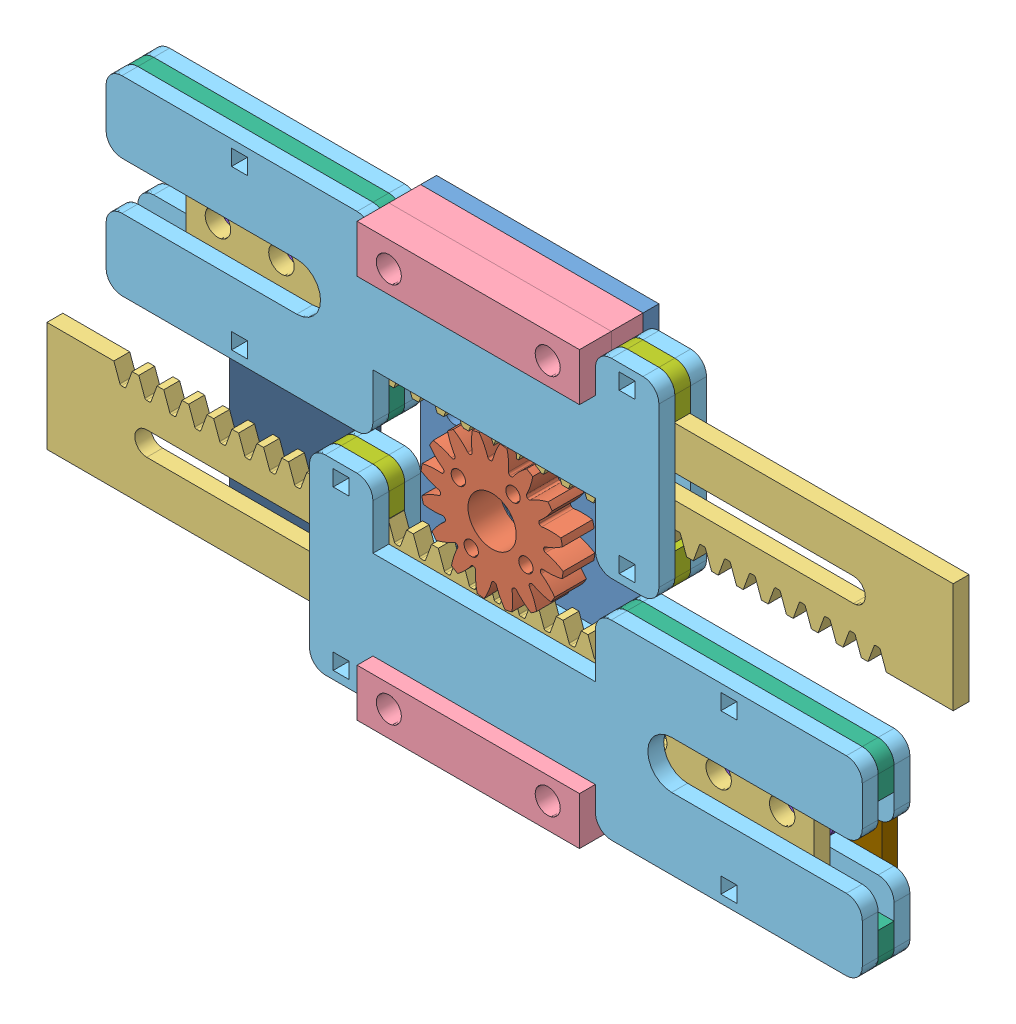
SolidWorks assembly Rack Assembl, configuration Default. Lengths in mm.
Overall size (181.1 86.36 22.23).
25 component instances, 11 part files, 74 mates.
Components (placement in the parent):
- NewBackboard-1: NewBackboard [По умолчанию] at (132.1592 -2.6593 45.9853) size (44.45 86.36 3.17)
- Gear (Original)-1: Gear (Original) [5172T63] at (132.1592 40.5207 40.5878) x (0.999384 0.035107 0) z (0 0 1) size (406.4 28.57 16.51)
- Rack-1: Rack [5174T2] at (-135.3035 19.3371 45.9853) size (153.29 22 3.18)
- Rack-2: Rack [5174T2] at (399.6219 61.7043 45.9853) x (-1 0 0) z (0 0 1) size (153.29 22 3.18)
- Support-1: Support [По умолчанию] at (256.738 55.3465 61.8603) x (1 0 0) z (0 0 -1) size (44.45 9.52 6.35)
- Support-2: Support [По умолчанию] at (256.738 55.3465 55.5103) x (1 0 0) z (0 0 -1) size (44.45 9.52 6.35)
- Support-3: Support [По умолчанию] at (256.738 25.695 55.5103) size (44.45 9.52 6.35)
- Support-4: Support [По умолчанию] at (256.738 25.695 49.1603) size (44.45 9.52 6.35)
- RackGuide-10: RackGuide [Default] at (154.3842 6.8657 49.1603) size (110.49 38.1 3.17)
- RackGuide-13: RackGuide [Default] at (154.3842 6.8657 55.5103) size (110.49 38.1 3.17)
- RackGuide-14: RackGuide [Default] at (109.9342 74.1757 55.5103) x (-1 0 0) z (0 0 1) size (110.49 38.1 3.17)
- RackGuide-15: RackGuide [Default] at (109.9342 74.1757 49.1603) x (-1 0 0) z (0 0 1) size (110.49 38.1 3.17)
- Support 1-2: Support 1 [Default] at (144.2242 8.9739 52.3353) size (53.34 7.87 3.17)
- Support 1-3: Support 1 [Default] at (120.0942 72.0675 52.3353) x (-1 0 0) z (0 0 1) size (53.34 7.87 3.17)
- Small Support-1: Small Support [Default] at (154.3842 74.3535 52.3353) size (12.7 7.87 3.17)
- Small Support-2: Small Support [Default] at (154.3842 52.0015 55.5103) x (1 0 0) z (0 0 -1) size (12.7 7.87 3.17)
- Small Support-3: Small Support [Default] at (97.2342 29.0399 52.3353) size (12.7 7.87 3.17)
- Small Support-4: Small Support [Default] at (109.9342 6.6879 52.3353) x (-1 0 0) z (0 0 1) size (12.7 7.87 3.17)
- PillSpacer-1: PillSpacer [Default] at (182.1965 17.8639 52.3353) x (1 0 0) z (0 0 -1) size (27.13 9.32 6.35)
- PillSpacer-2: PillSpacer [Default] at (82.1219 63.1775 52.3353) x (1 0 0) z (0 0 -1) size (27.13 9.32 6.35)
- SmallAdapter-1: SmallAdapter [Default] at (182.1965 17.9655 42.8103) x (1 0 0) z (0 0 -1) size (27.13 25.18 3.17)
- Long Adapter-1: Long Adapter [Default] at (82.1219 63.1775 45.9853) x (1 0 0) z (0 0 -1) size (27.13 70.5 3.17)
- Support 1-4: Support 1 [Default] at (144.2242 26.7539 55.5103) x (1 0 0) z (0 0 -1) size (53.34 7.87 3.17)
- Support 1-5: Support 1 [Default] at (46.4342 54.2875 52.3353) size (53.34 7.87 3.17)
- Small Spacer-1: Small Spacer [По умолчанию] at (182.1965 17.8639 45.9853) x (1 0 0) z (0 0 -1) size (27.13 9.32 3.17)
Mates (geometry in assembly coordinates):
- Concentric1: concentric anti-aligned: cylinder of NewBackboard-1 through (132.1592 40.5207 49.1603) axis (0 0 -1) radius 6.75; cylinder of Gear-1 through (132.1592 40.5207 28.3548) axis (0 0 1) radius 4.826
- Concentric2: concentric aligned: cylinder of NewBackboard-1 through (116.2842 78.6207 49.1603) axis (0 0 -1) radius 2.5082; cylinder of Support-4 through (116.2842 78.6207 55.5103) axis (0 0 -1) radius 2.5082
- Concentric3: concentric aligned: cylinder of Support-3 through (116.2842 78.6207 61.8603) axis (0 0 -1) radius 2.5082; cylinder of Support-4 through (116.2842 78.6207 55.5103) axis (0 0 -1) radius 2.5082
- Coincident1: coincident anti-aligned: plane of Support-3 through (256.738 25.695 55.5103) normal (0 0 -1); plane of Support-4 through (256.738 25.695 55.5103) normal (0 0 1)
- Coincident2: coincident anti-aligned: plane of NewBackboard-1 through (132.1592 -2.6593 49.1603) normal (0 0 1); plane of Support-4 through (256.738 25.695 49.1603) normal (0 0 -1)
- Concentric4: concentric aligned: circle of Backboard1-1; circle of Support-3
- Concentric5: concentric aligned: cylinder of Support-3 through (148.0342 78.6207 61.8603) axis (0 0 -1) radius 2.5082; cylinder of Support-4 through (148.0342 78.6207 55.5103) axis (0 0 -1) radius 2.5082
- Concentric6: concentric anti-aligned: cylinder of NewBackboard-1 through (148.0342 2.4207 49.1603) axis (0 0 -1) radius 2.5082; cylinder of Support-2 through (148.0342 2.4207 49.1603) axis (0 0 1) radius 2.5082
- Concentric7: concentric anti-aligned: cylinder of NewBackboard-1 through (116.2842 2.4207 49.1603) axis (0 0 -1) radius 2.5082; cylinder of Support-2 through (116.2842 2.4207 49.1603) axis (0 0 1) radius 2.5082
- Coincident3: coincident anti-aligned: plane of NewBackboard-1 through (132.1592 -2.6593 49.1603) normal (0 0 1); plane of Support-2 through (256.738 55.3465 49.1603) normal (0 0 -1)
- Coincident4: coincident anti-aligned: plane of Support-1 through (256.738 55.3465 55.5103) normal (0 0 -1); plane of Support-2 through (256.738 55.3465 55.5103) normal (0 0 1)
- Concentric8: concentric aligned: cylinder of Support-1 through (116.2842 2.4207 55.5103) axis (0 0 1) radius 2.5082; cylinder of Support-2 through (116.2842 2.4207 49.1603) axis (0 0 1) radius 2.5082
- Concentric9: concentric aligned: cylinder of Support-1 through (148.0342 2.4207 55.5103) axis (0 0 1) radius 2.5082; cylinder of Support-2 through (148.0342 2.4207 49.1603) axis (0 0 1) radius 2.5082
- Coincident5: coincident anti-aligned: plane of Rack-1 through (-135.3035 6.8657 45.9853) normal (0 -1 0); plane of Support-1 through (109.9342 6.8657 55.5103) normal (0 1 0)
- Coincident6: coincident anti-aligned: plane of Rack-2 through (399.6219 74.1757 45.9853) normal (0 1 0); plane of Support-3 through (109.9342 74.1757 61.8603) normal (0 -1 0)
- Parallel1: parallel aligned: plane of Rack-1 through (169.4965 28.8621 55.5103) normal (0 0 1); plane of Rack-2 through (94.8219 52.1793 55.5103) normal (0 0 1)
- Distance1: distance = 3.175 mm anti-aligned: plane of Rack-2 through (399.6219 61.7043 52.3353) normal (0 0 -1); plane of NewBackboard-1 through (132.1592 -2.6593 49.1603) normal (0 0 1)
- Distance3: distance = 1.5875 mm anti-aligned: plane of Gear-1 through (132.1592 40.5207 50.7478) normal (0 0 -1); plane of NewBackboard-1 through (132.1592 -2.6593 49.1603) normal (0 0 1)
- Distance4: distance = 3.175 mm anti-aligned: plane of Rack-1 through (-135.3035 19.3371 52.3353) normal (0 0 -1); plane of NewBackboard-1 through (132.1592 -2.6593 49.1603) normal (0 0 1)
- Coincident38: coincident anti-aligned: plane of Support-2 through (109.9342 6.8657 49.1603) normal (0 1 0); plane of RackGuide-10 through (109.9342 6.8657 52.3353) normal (0 -1 0)
- Coincident39: coincident anti-aligned: plane of NewBackboard-1 through (109.9342 32.9007 49.1603) normal (-1 0 0); plane of RackGuide-10 through (109.9342 1.9889 52.3353) normal (1 0 0)
- Coincident44: coincident anti-aligned: plane of NewBackboard-1 through (132.1592 -2.6593 49.1603) normal (0 0 1); plane of RackGuide-10 through (157.5592 1.9889 49.1603) normal (0 0 -1)
- Coincident48: coincident anti-aligned: plane of Rack-1 through (169.4965 28.8621 55.5103) normal (0 0 1); plane of RackGuide-13 through (157.5592 1.9889 55.5103) normal (0 0 -1)
- Coincident51: coincident anti-aligned: plane of NewBackboard-1 through (132.1592 -2.6593 49.1603) normal (0 0 1); plane of RackGuide-15 through (106.7592 79.0525 49.1603) normal (0 0 -1)
- Coincident52: coincident anti-aligned: plane of Support-4 through (154.3842 74.1757 55.5103) normal (1 0 0); plane of RackGuide-15 through (154.3842 79.0525 52.3353) normal (-1 0 0)
- Coincident55: coincident aligned: plane of RackGuide-14 through (167.0842 47.3025 58.6853) normal (1 0 0); plane of RackGuide-15 through (167.0842 47.3025 52.3353) normal (1 0 0)
- Coincident56: coincident aligned: plane of RackGuide-14 through (163.9092 82.2275 58.6853) normal (0 1 0); plane of RackGuide-15 through (163.9092 82.2275 52.3353) normal (0 1 0)
- Coincident57: coincident anti-aligned: plane of Rack-2 through (94.8219 52.1793 55.5103) normal (0 0 1); plane of RackGuide-14 through (106.7592 79.0525 55.5103) normal (0 0 -1)
- Coincident62: coincident anti-aligned: plane of Support-1 through (109.9342 6.8657 55.5103) normal (0 1 0); plane of RackGuide-13 through (109.9342 6.8657 58.6853) normal (0 -1 0)
- Coincident63: coincident anti-aligned: plane of Support-1 through (154.3842 6.8657 55.5103) normal (1 0 0); plane of RackGuide-13 through (154.3842 6.8657 58.6853) normal (-1 0 0)
- Coincident64: coincident aligned: plane of RackGuide-13 through (179.4667 3.5764 55.5103) normal (0 -1 0); plane of Support 1-2 through (182.6417 3.5764 55.5103) normal (0 -1 0)
- Coincident65: coincident aligned: plane of RackGuide-13 through (179.4667 0.4014 55.5103) normal (1 0 0); plane of Support 1-2 through (179.4667 3.5764 55.5103) normal (1 0 0)
- Coincident66: coincident anti-aligned: plane of RackGuide-13 through (157.5592 1.9889 55.5103) normal (0 0 -1); plane of Support 1-2 through (204.5492 1.9889 55.5103) normal (0 0 1)
- Coincident67: coincident aligned: plane of RackGuide-15 through (106.7592 82.2275 52.3353) normal (0 1 0); plane of Support 1-3 through (59.7692 82.2275 55.5103) normal (0 1 0)
- Coincident68: coincident aligned: plane of RackGuide-14 through (84.8517 77.465 55.5103) normal (0 1 0); plane of Support 1-3 through (81.6767 77.465 55.5103) normal (0 1 0)
- Coincident69: coincident aligned: plane of RackGuide-14 through (84.8517 80.64 55.5103) normal (-1 0 0); plane of Support 1-3 through (84.8517 77.465 55.5103) normal (-1 0 0)
- Coincident70: coincident anti-aligned: plane of RackGuide-15 through (106.7592 79.0525 52.3353) normal (0 0 1); plane of Support 1-3 through (59.7692 79.0525 52.3353) normal (0 0 -1)
- Coincident71: coincident anti-aligned: plane of RackGuide-15 through (106.7592 79.0525 52.3353) normal (0 0 1); plane of Small Support-2 through (157.5592 47.3025 52.3353) normal (0 0 -1)
- Coincident72: coincident aligned: plane of RackGuide-14 through (162.3217 45.715 55.5103) normal (-1 0 0); plane of Small Support-2 through (162.3217 45.715 52.3353) normal (-1 0 0)
- Coincident73: coincident aligned: plane of RackGuide-15 through (157.5592 44.1275 52.3353) normal (0 -1 0); plane of Small Support-2 through (157.5592 44.1275 52.3353) normal (0 -1 0)
- Coincident74: coincident anti-aligned: plane of RackGuide-14 through (106.7592 79.0525 55.5103) normal (0 0 -1); plane of Small Support-1 through (157.5592 79.0525 55.5103) normal (0 0 1)
- Coincident75: coincident aligned: plane of RackGuide-14 through (159.1467 80.64 55.5103) normal (1 0 0); plane of Small Support-1 through (159.1467 80.64 55.5103) normal (1 0 0)
- Coincident76: coincident aligned: plane of RackGuide-14 through (163.9092 82.2275 58.6853) normal (0 1 0); plane of Small Support-1 through (157.5592 82.2275 55.5103) normal (0 1 0)
- Coincident77: coincident aligned: plane of RackGuide-13 through (101.9967 35.3264 55.5103) normal (1 0 0); plane of Small Support-3 through (101.9967 35.3264 55.5103) normal (1 0 0)
- Coincident78: coincident aligned: plane of RackGuide-13 through (105.1717 0.4014 55.5103) normal (-1 0 0); plane of Small Support-4 through (105.1717 0.4014 55.5103) normal (-1 0 0)
- Coincident79: coincident anti-aligned: plane of RackGuide-10 through (157.5592 1.9889 52.3353) normal (0 0 1); plane of Small Support-4 through (106.7592 1.9889 52.3353) normal (0 0 -1)
- Coincident80: coincident aligned: plane of RackGuide-10 through (100.4092 -1.1861 52.3353) normal (0 -1 0); plane of Small Support-4 through (106.7592 -1.1861 55.5103) normal (0 -1 0)
- Coincident81: coincident aligned: plane of RackGuide-13 through (106.7592 36.9139 58.6853) normal (0 1 0); plane of Small Support-3 through (100.4092 36.9139 55.5103) normal (0 1 0)
- Coincident82: coincident anti-aligned: plane of RackGuide-10 through (157.5592 1.9889 52.3353) normal (0 0 1); plane of Small Support-3 through (100.4092 33.7389 52.3353) normal (0 0 -1)
- Concentric16: concentric aligned: cylinder of Rack-1 through (188.5465 17.8639 52.3353) axis (0 0 -1) radius 2.5527; cylinder of PillSpacer-1 through (188.5465 17.8639 45.9853) axis (0 0 -1) radius 2.5527
- Concentric17: concentric aligned: cylinder of Rack-1 through (175.8465 17.8639 52.3353) axis (0 0 -1) radius 2.5527; cylinder of PillSpacer-1 through (175.8465 17.8639 45.9853) axis (0 0 -1) radius 2.5527
- Coincident86: coincident anti-aligned: plane of Rack-1 through (-135.3035 19.3371 52.3353) normal (0 0 -1); plane of PillSpacer-1 through (191.0992 17.8639 52.3353) normal (0 0 1)
- Concentric18: concentric aligned: cylinder of Rack-2 through (75.7719 63.1775 52.3353) axis (0 0 -1) radius 2.5527; cylinder of PillSpacer-2 through (75.7719 63.1775 45.9853) axis (0 0 -1) radius 2.5527
- Concentric19: concentric aligned: cylinder of Rack-2 through (88.4719 63.1775 52.3353) axis (0 0 -1) radius 2.5527; cylinder of PillSpacer-2 through (88.4719 63.1775 45.9853) axis (0 0 -1) radius 2.5527
- Coincident87: coincident anti-aligned: plane of Rack-2 through (399.6219 61.7043 52.3353) normal (0 0 -1); plane of PillSpacer-2 through (91.0246 63.1775 52.3353) normal (0 0 1)
- InPlace6: in place: plane of ? through (95.3877 63.1775 45.9853) normal (0 0 -1); plane of ? through (0 0 45.9853) normal (0 0 -1); moOrthogonalPlaneRef_w of ? through (95.3877 63.1775 45.9853) normal (0 0 -1); plane of ? through (0 0 45.9853) normal (0 1 0); plane of ? through (95.3877 63.1775 45.9853) normal (0 0 -1); plane of ? through (0 0 45.9853) normal (-1 0 0); plane of PillSpacer-2 through (91.0246 63.1775 45.9853) normal (0 0 -1); unknown of Long Adapter-1
- Coincident91: coincident aligned: plane of PillSpacer-2; plane of Long Adapter-1
- Coincident92: coincident aligned: moOrthogonalPlaneRef_w of PillSpacer-2 through (82.1219 63.1775 45.9853) normal (0 -1 0); plane of Part9^Rack Assembl-1 through (82.1219 63.1775 45.9853) normal (0 -1 0)
- Coincident93: coincident anti-aligned: moOrthogonalPlaneRef_w of PillSpacer-2 through (82.1219 63.1775 45.9853) normal (-1 0 0); plane of Part9^Rack Assembl-1 through (82.1219 63.1775 45.9853) normal (1 0 0)
- Coincident94: coincident anti-aligned: plane of RackGuide-13 through (157.5592 1.9889 55.5103) normal (0 0 -1); plane of Support 1-4 through (204.5492 33.7389 55.5103) normal (0 0 1)
- Coincident95: coincident aligned: plane of RackGuide-10 through (182.6417 35.3264 49.1603) normal (-1 0 0); plane of Support 1-4 through (182.6417 35.3264 52.3353) normal (-1 0 0)
- Coincident96: coincident aligned: plane of RackGuide-10 through (179.4667 35.3264 49.1603) normal (0 -1 0); plane of Support 1-4 through (179.4667 35.3264 52.3353) normal (0 -1 0)
- Coincident97: coincident aligned: plane of RackGuide-15 through (81.6767 45.715 49.1603) normal (1 0 0); plane of Support 1-5 through (81.6767 48.89 55.5103) normal (1 0 0)
- Coincident98: coincident aligned: plane of RackGuide-15 through (84.8517 48.89 49.1603) normal (0 -1 0); plane of Support 1-5 through (84.8517 48.89 55.5103) normal (0 -1 0)
- Coincident99: coincident anti-aligned: plane of RackGuide-15 through (106.7592 79.0525 52.3353) normal (0 0 1); plane of Support 1-5 through (106.7592 47.3025 52.3353) normal (0 0 -1)
- Linear/Linear Coupler3: linear coupler = 25.4 : 25.4 mm: plane of RackGuide-10 through (97.2342 33.7389 52.3353) normal (-1 0 0); plane of RackGuide-15 through (167.0842 47.3025 52.3353) normal (1 0 0)
- Coincident103: coincident anti-aligned: plane of Support-3 through (109.9342 74.1757 61.8603) normal (0 -1 0); plane of RackGuide-14 through (154.3842 74.1757 58.6853) normal (0 1 0)
- На месте2: unknown: plane of ? through (189.7539 17.8639 45.9853) normal (0 0 -1); plane of ? through (0 0 45.9853) normal (0 0 -1); plane of ? through (189.7539 17.8639 45.9853) normal (0 0 -1); plane of ? through (0 0 45.9853) normal (0 1 0); plane of ? through (189.7539 17.8639 45.9853) normal (0 0 -1); plane of ? through (0 0 45.9853) normal (-1 0 0); plane of PillSpacer-1 through (191.0992 17.8639 45.9853) normal (0 0 -1); unknown of Small Spacer-1
- Совпадение4: coincident aligned: plane of PillSpacer-1; plane of Small Spacer-1
- Совпадение5: coincident aligned: moOrthogonalPlaneRef_w of PillSpacer-1 through (182.1965 17.8639 45.9853) normal (0 -1 0); plane of Деталь2^Rack Assembl-1 through (182.1965 17.8639 45.9853) normal (0 -1 0)
- Совпадение6: coincident anti-aligned: moOrthogonalPlaneRef_w of PillSpacer-1 through (182.1965 17.8639 45.9853) normal (-1 0 0); plane of Деталь2^Rack Assembl-1 through (182.1965 17.8639 45.9853) normal (1 0 0)
- Концентричный1: concentric anti-aligned: cylinder of SmallAdapter-1 through (175.8465 17.8639 39.6353) axis (0 0 -1) radius 2.5527; cylinder of Small Spacer-1 through (175.8465 17.8639 42.8103) axis (0 0 1) radius 2.5527
- Концентричный2: concentric anti-aligned: cylinder of SmallAdapter-1 through (188.5465 17.8639 39.6353) axis (0 0 -1) radius 2.5527; cylinder of Small Spacer-1 through (188.5465 17.8639 42.8103) axis (0 0 1) radius 2.5527
- Совпадение7: coincident anti-aligned: plane of SmallAdapter-1 through (182.1965 17.9655 42.8103) normal (0 0 1); plane of Small Spacer-1 through (191.0992 17.8639 42.8103) normal (0 0 -1)
